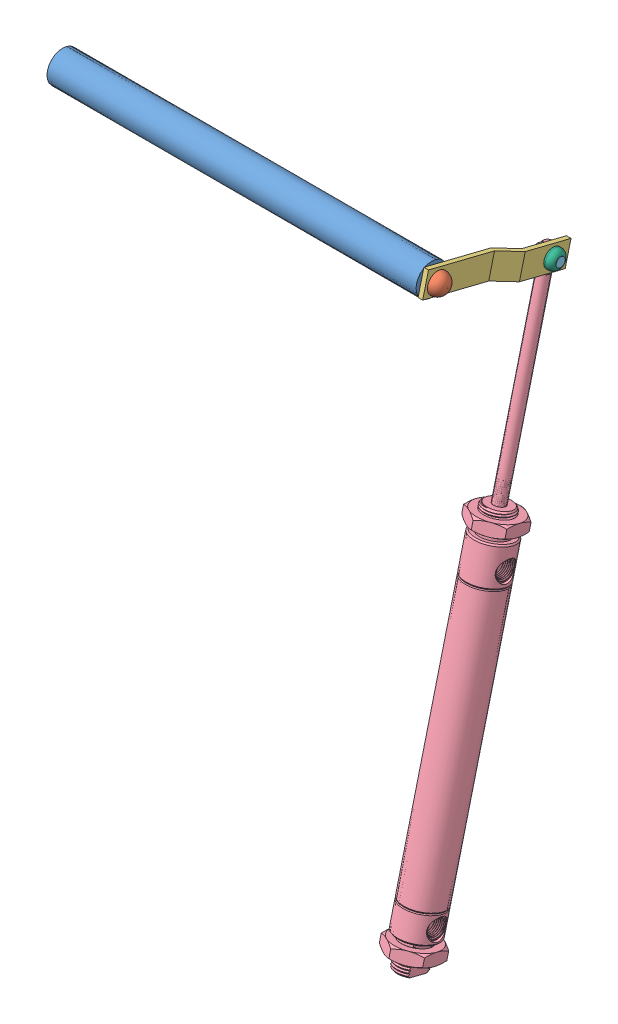
SolidWorks assembly Main Valve Final, configuration Default. Lengths in mm.
Overall size (220.6 330.15 103.84).
6 component instances, 6 part files, 12 mates.
Components (placement in the parent):
- Main Valve Shaft-1: Main Valve Shaft [Default] at (-14.5668 127.1951 189.3128) size (203.2 17.27 17.27)
- Shaft Screw-1: Shaft Screw [Default] at (191.9352 127.1951 189.3128) x (0 -0.38357 -0.923512) z (-1 0 0) size (11.36 11.36 11.68)
- Handle-1: Handle [Default] at (188.6332 122.2662 196.84) x (0 -0.242002 -0.970276) z (1 0 0) size (74.57 13.21 8.67)
- 6498K636_Round Body Air Cylinder (1)-1: 6498K636_Round Body Air Cylinder (1) [6498K636] at (194.1271 -85.6318 180.8185) x (0 -0.970276 0.242002) z (1 0 0) size (318.84 27.5 23.81)
- Piston Screw-1: Piston Screw [Default] at (191.3799 112.7099 131.2362) x (0 -0.024294 -0.999705) z (1 0 0) size (7.62 7.62 13.97)
- Piston Washer-2: Piston Washer [Default] at (197.3021 112.7099 131.2362) x (0 0 -1) z (1 0 0) size (10.16 10.16 4.06)
Mates (geometry in assembly coordinates):
- Concentric1: concentric anti-aligned: circle of Main Valve Shaft-1; circle of Shaft Screw-1
- Distance2: distance = 3.302 mm anti-aligned: plane of Shaft Screw-1 through (191.9352 127.1951 189.3128) normal (-1 0 0); plane of Main Valve Shaft-1 through (188.6332 127.1951 189.3128) normal (1 0 0)
- Distance3: distance = 0 mm anti-aligned: plane of Handle-1 through (188.6332 135.0816 193.6436) normal (-1 0 0); plane of Main Valve Shaft-1 through (188.6332 127.1951 189.3128) normal (1 0 0)
- Parallel1: parallel anti-aligned: plane of Shaft Screw-1 through (191.9352 127.1951 189.3128) normal (-1 0 0); plane of Handle-1 through (191.1732 135.0816 193.6436) normal (1 0 0)
- Distance5: distance = 0 mm: cylinder of Handle-1 through (197.3031 127.1951 189.3128) axis (-1 0 0) radius 3.048; cylinder of Shaft Screw-1 through (185.5852 127.1951 189.3128) axis (1 0 0) radius 4.3688
- Parallel2: parallel aligned: plane of Handle-1 through (197.3021 123.1641 145.8621) normal (1 0 0); plane of 6498K636_Round Body Air Cylinder (1)-1 through (206.0333 -3.7488 153.3109) normal (1 0 0)
- Parallel3: parallel anti-aligned: line of Handle-1 through (191.1732 126.0102 157.2731) axis (0 -0.970276 0.242002); line of 6498K636_Round Body Air Cylinder (1)-1 through (206.0333 -2.717 153.0536) axis (0 0.970276 -0.242002)
- Tangent14: tangent: circle of Handle-1; curve of 6498K636_Round Body Air Cylinder (1)-1
- Concentric4: concentric anti-aligned: cylinder of Handle-1 through (188.6322 112.7099 131.2362) axis (1 0 0) radius 2.54; cylinder of Piston Screw-1 through (201.5399 112.7099 131.2362) axis (-1 0 0) radius 2.54
- Distance9: distance = 3.3821 mm anti-aligned: plane of Handle-1 through (194.7621 123.1641 145.8621) normal (-1 0 0); plane of Piston Screw-1 through (191.3799 112.7099 131.2362) normal (1 0 0)
- Coincident4: coincident anti-aligned: plane of Handle-1 through (197.3021 123.1641 145.8621) normal (1 0 0); plane of Piston Washer-2 through (197.3021 112.7099 131.2362) normal (-1 0 0)
- Concentric5: concentric anti-aligned: cylinder of Piston Screw-1 through (201.5399 112.7099 131.2362) axis (-1 0 0) radius 2.54; cylinder of Piston Washer-2 through (197.3021 112.7099 131.2362) axis (1 0 0) radius 2.54
